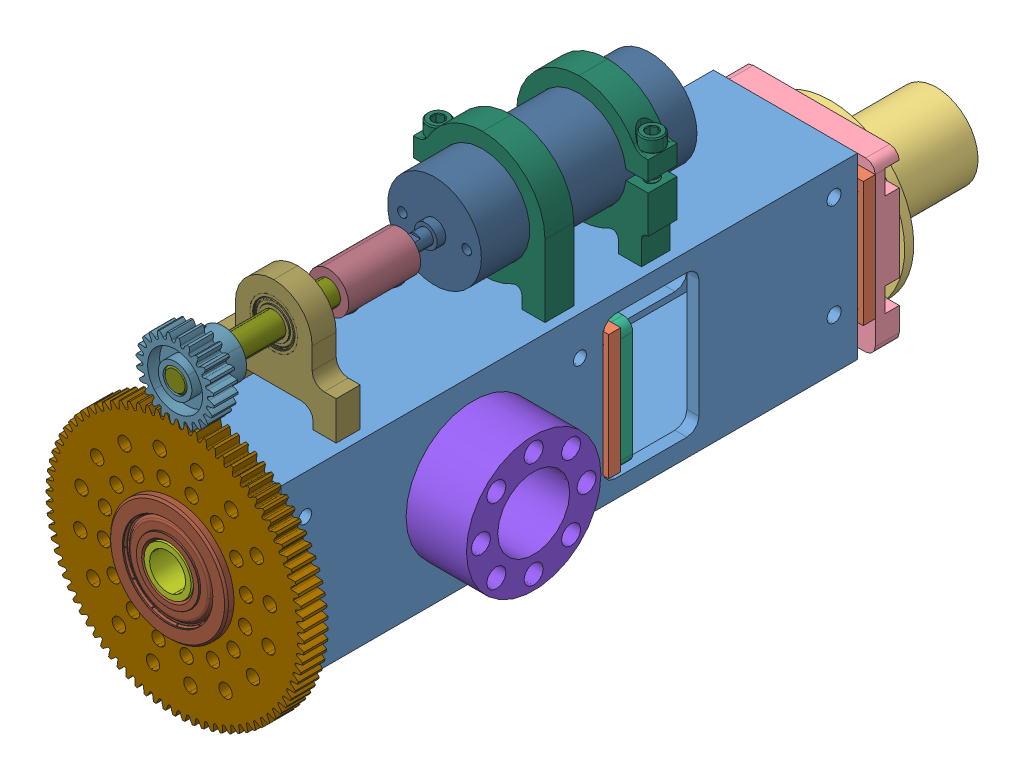
SolidWorks assembly Link 3 final, configuration Default. Lengths in mm.
Overall size (82.13 100.25 203.31).
24 component instances, 16 part files, 59 mates.
Components (placement in the parent):
- L3v1 Base-1: L3v1 Base [Default] at (8.4803 58.2755 10.2579) x (1 0 0) z (0 -1 0) size (38.1 152.4 47.24)
- J2v2 Angle Bracket 585508-2: J2v2 Angle Bracket 585508 [Default] at (-8.1567 59.6725 10.2579) x (0 1 0) z (-1 0 0) size (33.02 12.43 7.88)
- 12 wire slip ring-1: 12 wire slip ring [Default] at (8.4803 56.4975 -1.6671) x (0.999999 -0.001711 0) z (-0.001711 -0.999999 0) size (44 39.4 44)
- L3v1 SlipRingBlock-2: L3v1 SlipRingBlock [Default] at (8.4803 56.4975 7.0829) x (-1 0 0) z (0 -1 0) size (41.15 6.35 44.45)
- 0.5 oilite bushing-1: 0.5 oilite bushing [6338K572] at (8.4803 58.2755 69.6304) x (1 0 0) z (0 -1 0) size (22.23 12.7 22.23)
- J2v2 Angle Bracket 585508-3: J2v2 Angle Bracket 585508 [Default] at (25.1173 58.2755 77.5679) x (0 -1 0) z (1 0 0) size (33.02 12.43 7.88)
- J2v2 Angle Bracket 585508-4: J2v2 Angle Bracket 585508 [Default] at (-8.1567 58.2755 77.5679) x (0 1 0) z (-1 0 0) size (33.02 12.43 7.88)
- L3v1 Bushing Support-1: L3v1 Bushing Support [Default] at (8.4803 58.2755 71.2179) x (1 0 0) z (0 -1 0) size (41.15 3.17 33.02)
- J2v2 Angle Bracket 585508-1: J2v2 Angle Bracket 585508 [Default] at (25.1173 59.6725 10.2579) x (0 -1 0) z (1 0 0) size (33.02 12.43 7.88)
- Link3 to 4 Shaft-1: Link3 to 4 Shaft [Default] at (8.4803 58.2755 120.6844) x (0 0 -1) z (0.883354 -0.468706 0) size (105.92 12.45 12.45)
- L3v1 Spacer-1: L3v1 Spacer [Default] at (43.5069 58.2755 111.8579) x (0 1 0) z (0 0 1) size (35.56 15.98 35.56)
- 0.5 oilite bushing-2: 0.5 oilite bushing [6338K572] at (8.4803 58.2755 170.7148) x (1 0 0) z (0 1 0) size (22.23 12.7 22.23)
- 84T 32DP 1in bore plate gear-1: 84T 32DP 1in bore plate gear [Default] at (8.4803 58.2755 171.6622) x (-0.229974 -0.973197 0) z (0 0 -1) size (68.26 68.26 6.35)
- 56 rpm motor-1: 56 rpm motor [Default] at (8.4803 100.9475 103.0622) x (0 0 1) z (-1 0 0) size (74.8 24.8 24.8)
- L3v1 Bushing Support-2: L3v1 Bushing Support [Default] at (8.4803 58.2755 169.1273) x (1 0 0) z (0 1 0) size (41.15 3.17 33.02)
- J2v2 Angle Bracket 585508-9: J2v2 Angle Bracket 585508 [Default] at (-8.1567 58.2755 162.6579) x (0 -1 0) z (-1 0 0) size (33.02 12.43 7.88)
- J2v2 Angle Bracket 585508-10: J2v2 Angle Bracket 585508 [Default] at (25.1173 58.2755 162.6579) x (0 1 0) z (1 0 0) size (33.02 12.43 7.88)
- .5ID 1.125OD Flange Bearing-1: .5ID 1.125OD Flange Bearing [Default] at (8.4803 58.2755 165.7059) x (-0.115864 -0.993265 0) z (-0.993265 0.115864 0) size (31.17 7.94 31.17)
- quarter in  bearing-1: quarter in  bearing [Default] at (0.1036 124.4796 125.9706) x (1 0 0) z (0 -1 0) size (33.02 6.35 29.21)
- 4mm to quarter in coupler-1: 4mm to quarter in coupler [Default] at (-87.7616 108.8102 138.0956) x (-0.955138 -0.296162 0) z (0.296162 -0.955138 0) size (10.67 19.05 10.67)
- 24T quarter inch gear hub-1: 24T quarter inch gear hub [Default] at (36.9204 99.2447 166.1829) x (0.761841 0.647764 0) z (0 0 1) size (20.64 20.64 12.7)
- 25mm motor mount-1: 25mm motor mount [Default] at (35.0627 111.6687 83.0668) x (1 0 0) z (0 -1 0) size (34.9 7.62 35.56)
- 25mm motor mount-2: 25mm motor mount [Default] at (-18.1021 111.6687 64.5336) x (-1 0 0) z (0 -1 0) size (34.9 7.62 35.56)
- quarter in shaft 2in-2: quarter in shaft 2in [Default] at (8.4803 100.9475 120.8622) x (0.375221 0.926936 0) z (0.926936 -0.375221 0) size (6.34 50.8 6.34)
Mates (geometry in assembly coordinates):
- Coincident5: coincident anti-aligned: plane of L3v1 Base-1 through (8.4803 58.2755 10.2579) normal (0 0 -1); plane of J2v2 Angle Bracket 585508-1 through (25.1173 59.6725 10.2579) normal (0 0 1)
- Coincident7: coincident anti-aligned: plane of L3v1 Base-1 through (24.3553 37.8285 162.6579) normal (-1 0 0); plane of J2v2 Angle Bracket 585508-1 through (24.3553 49.2433 19.5136) normal (1 0 0)
- Coincident8: coincident anti-aligned: plane of L3v1 Base-1 through (-7.3947 37.8285 162.6579) normal (1 0 0); plane of J2v2 Angle Bracket 585508-2 through (-7.3947 70.1018 19.5136) normal (-1 0 0)
- Coincident9: coincident anti-aligned: plane of L3v1 Base-1 through (8.4803 58.2755 10.2579) normal (0 0 -1); plane of J2v2 Angle Bracket 585508-2 through (-8.1567 59.6725 10.2579) normal (0 0 1)
- Coincident10: coincident aligned: plane of J2v2 Angle Bracket 585508-1 through (29.0543 76.1825 7.0829) normal (0 1 0); plane of J2v2 Angle Bracket 585508-2 through (-12.0937 76.1825 7.0829) normal (0 1 0)
- Distance2: distance = 5.715 mm aligned: plane of J2v2 Angle Bracket 585508-1 through (29.0543 76.1825 7.0829) normal (0 1 0); plane of L3v1 Base-1 through (-10.5697 81.8975 162.6579) normal (0 1 0)
- Coincident16: coincident anti-aligned: plane of J2v2 Angle Bracket 585508-1 through (25.1173 59.6725 7.0829) normal (0 0 -1); plane of L3v1 SlipRingBlock-2 through (8.4803 56.4975 7.0829) normal (0 0 1)
- Concentric4: concentric anti-aligned: circle of J2v2 Angle Bracket 585508-1; cylinder of L3v1 SlipRingBlock-2 through (25.8793 73.1429 0.7329) axis (0 0 -1) radius 1.8986
- Concentric5: concentric anti-aligned: circle of J2v2 Angle Bracket 585508-2; circle of L3v1 SlipRingBlock-2
- Coincident17: coincident anti-aligned: plane of 12 wire slip ring-1 through (8.4803 56.4975 0.7329) normal (0 0 1); plane of L3v1 SlipRingBlock-2 through (8.4803 56.4975 0.7329) normal (0 0 -1)
- Concentric6: concentric anti-aligned: cylinder of 12 wire slip ring-1 through (8.4803 56.4975 -29.6671) axis (0 0 1) radius 11; cylinder of L3v1 SlipRingBlock-2 through (8.4803 56.4975 7.0829) axis (0 0 -1) radius 11.43
- Coincident22: coincident anti-aligned: plane of L3v1 Base-1 through (-7.3947 37.8285 162.6579) normal (1 0 0); plane of J2v2 Angle Bracket 585508-4 through (-7.3947 68.7048 86.8236) normal (-1 0 0)
- Coincident23: coincident anti-aligned: plane of L3v1 Base-1 through (-7.3947 42.591 77.5679) normal (0 0 -1); plane of J2v2 Angle Bracket 585508-4 through (-8.1567 58.2755 77.5679) normal (0 0 1)
- Width2: width aligned: plane of J2v2 Angle Bracket 585508-4 through (-12.0937 74.7855 74.3929) normal (0 1 0); plane of J2v2 Angle Bracket 585508-4 through (-12.0937 41.7655 74.3929) normal (0 -1 0); plane of L3v1 Base-1 through (-10.5697 81.8975 162.6579) normal (0 1 0); plane of L3v1 Base-1 through (-10.5697 34.6535 162.6579) normal (0 -1 0)
- Coincident24: coincident anti-aligned: plane of L3v1 Base-1 through (24.3553 37.8285 162.6579) normal (-1 0 0); plane of J2v2 Angle Bracket 585508-3 through (24.3553 68.7048 86.8236) normal (1 0 0)
- Coincident25: coincident aligned: plane of J2v2 Angle Bracket 585508-3 through (25.1173 58.2755 74.3929) normal (0 0 -1); plane of J2v2 Angle Bracket 585508-4 through (-8.1567 58.2755 74.3929) normal (0 0 -1)
- Coincident26: coincident aligned: plane of J2v2 Angle Bracket 585508-3 through (29.0543 74.7855 74.3929) normal (0 1 0); plane of J2v2 Angle Bracket 585508-4 through (-12.0937 74.7855 74.3929) normal (0 1 0)
- Coincident27: coincident anti-aligned: plane of J2v2 Angle Bracket 585508-4 through (-8.1567 58.2755 74.3929) normal (0 0 -1); plane of L3v1 Bushing Support-1 through (26.5143 72.2455 74.3929) normal (0 0 1)
- Width3: width anti-aligned: plane of L3v1 Bushing Support-1 through (26.5143 74.7855 74.3929) normal (0 1 0); plane of L3v1 Bushing Support-1 through (26.5143 41.7655 74.3929) normal (0 -1 0); plane of J2v2 Angle Bracket 585508-4 through (-12.0937 41.7655 74.3929) normal (0 -1 0); plane of J2v2 Angle Bracket 585508-4 through (-12.0937 74.7855 74.3929) normal (0 1 0)
- Coincident28: coincident aligned: plane of J2v2 Angle Bracket 585508-4 through (-12.0937 41.7655 74.3929) normal (-1 0 0); plane of L3v1 Bushing Support-1 through (-12.0937 44.3055 74.3929) normal (-1 0 0)
- Coincident29: coincident anti-aligned: plane of 0.5 oilite bushing-1 through (8.4803 58.2755 71.2179) normal (0 0 1); plane of L3v1 Bushing Support-1 through (26.5143 72.2455 71.2179) normal (0 0 -1)
- Concentric7: concentric anti-aligned: cylinder of 0.5 oilite bushing-1 through (8.4803 58.2755 82.3304) axis (0 0 -1) radius 6.3627; cylinder of L3v1 Bushing Support-1 through (8.4803 58.2755 71.2179) axis (0 0 1) radius 7.9502
- Concentric8: concentric anti-aligned: cylinder of 0.5 oilite bushing-1 through (8.4803 58.2755 82.3304) axis (0 0 -1) radius 6.3627; cylinder of Link3 to 4 Shaft-1 through (8.4803 58.2755 67.7254) axis (0 0 1) radius 6.223
- Coincident30: coincident aligned: plane of 0.5 oilite bushing-1 through (8.4803 58.2755 69.6304) normal (0 0 -1); plane of Link3 to 4 Shaft-1 through (8.4803 58.2755 69.6304) normal (0 0 -1)
- Coincident31: coincident anti-aligned: plane of L3v1 Base-1 through (27.5303 34.6535 162.6579) normal (1 0 0); plane of L3v1 Spacer-1 through (27.5303 58.2755 111.8579) normal (-1 0 0)
- Concentric9: concentric anti-aligned: cylinder of L3v1 Base-1 through (27.5303 58.2755 111.8579) axis (-1 0 0) radius 9.525; cylinder of L3v1 Spacer-1 through (27.5303 58.2755 111.8579) axis (1 0 0) radius 9.525
- Concentric10: concentric anti-aligned: cylinder of L3v1 Base-1 through (27.5303 48.3973 121.7362) axis (-1 0 0) radius 2.5527; cylinder of L3v1 Spacer-1 through (27.5303 48.3973 121.7362) axis (1 0 0) radius 2.5527
- Concentric15: concentric anti-aligned: cylinder of Link3 to 4 Shaft-1 through (8.4803 58.2755 67.7254) axis (0 0 1) radius 6.223; cylinder of 84T 32DP 1in bore plate gear-1 through (8.4803 58.2755 171.6622) axis (0 0 -1) radius 14.2875
- Concentric18: concentric aligned: cylinder of Link3 to 4 Shaft-1 through (8.4803 58.2755 67.7254) axis (0 0 1) radius 6.223; cylinder of 0.5 oilite bushing-2 through (8.4803 58.2755 158.0148) axis (0 0 1) radius 6.3627
- Concentric22: concentric anti-aligned: cylinder of Link3 to 4 Shaft-1 through (8.4803 58.2755 67.7254) axis (0 0 1) radius 6.223; cylinder of 84T 32DP 1in bore plate gear-1 through (8.4803 58.2755 171.6622) axis (0 0 -1) radius 14.2875
- Concentric25: concentric anti-aligned: cylinder of 0.5 oilite bushing-2 through (8.4803 58.2755 158.0148) axis (0 0 1) radius 7.9502; cylinder of L3v1 Bushing Support-2 through (8.4803 58.2755 169.1273) axis (0 0 -1) radius 7.9502
- Parallel5: parallel aligned: plane of 12 wire slip ring-1 through (8.4803 56.4975 -29.6671) normal (0 0 -1); plane of 56 rpm motor-1 through (8.4803 100.9475 46.0622) normal (0 0 -1)
- Symmetric6: symmetric aligned: plane of L3v1 Base-1 through (27.5303 34.6535 162.6579) normal (1 0 0); plane of 56 rpm motor-1 through (-10.5697 34.6535 162.6579) normal (-1 0 0); plane of L3v1 Base-1 through (8.4803 100.9475 103.0622) normal (-1 0 0)
- Coincident68: coincident anti-aligned: plane of L3v1 Base-1 through (-7.3947 37.8285 162.6579) normal (1 0 0); plane of J2v2 Angle Bracket 585508-9 through (-7.3947 68.7048 153.4021) normal (-1 0 0)
- Coincident69: coincident aligned: plane of L3v1 Bushing Support-2 through (26.5143 74.7855 165.9523) normal (0 1 0); plane of J2v2 Angle Bracket 585508-9 through (-12.0937 74.7855 165.8329) normal (0 1 0)
- Coincident70: coincident anti-aligned: plane of L3v1 Base-1 through (8.4803 58.2755 162.6579) normal (0 0 1); plane of J2v2 Angle Bracket 585508-9 through (-8.1567 58.2755 162.6579) normal (0 0 -1)
- Coincident71: coincident anti-aligned: plane of L3v1 Base-1 through (24.3553 37.8285 162.6579) normal (-1 0 0); plane of J2v2 Angle Bracket 585508-10 through (24.3553 68.7048 153.4021) normal (1 0 0)
- Coincident72: coincident aligned: plane of L3v1 Bushing Support-2 through (26.5143 74.7855 165.9523) normal (0 1 0); plane of J2v2 Angle Bracket 585508-10 through (29.0543 74.7855 165.8329) normal (0 1 0)
- Coincident73: coincident anti-aligned: plane of L3v1 Base-1 through (8.4803 58.2755 162.6579) normal (0 0 1); plane of J2v2 Angle Bracket 585508-10 through (25.1173 58.2755 162.6579) normal (0 0 -1)
- Concentric31: concentric aligned: cylinder of 84T 32DP 1in bore plate gear-1 through (8.4803 58.2755 171.6622) axis (0 0 -1) radius 14.2875; cylinder of .5ID 1.125OD Flange Bearing-1 through (8.4803 58.2755 171.6622) axis (0 0 -1) radius 14.2875
- Coincident80: coincident anti-aligned: plane of 84T 32DP 1in bore plate gear-1 through (-24.2442 66.4973 171.6622) normal (0 0 1); plane of .5ID 1.125OD Flange Bearing-1 through (8.4803 58.2755 171.6622) normal (0 0 -1)
- Coincident86: coincident aligned: plane of Link3 to 4 Shaft-1 through (8.4803 58.2755 173.6434) normal (0 0 1); plane of .5ID 1.125OD Flange Bearing-1 through (8.4803 58.2755 173.6434) normal (0 0 1)
- Coincident91: coincident anti-aligned: plane of L3v1 Base-1 through (-10.5697 81.8975 162.6579) normal (0 1 0); plane of quarter in  bearing-1 through (24.9903 81.8975 145.5712) normal (0 -1 0)
- Concentric32: concentric aligned: cylinder of 56 rpm motor-1 through (8.4803 100.9475 46.0622) axis (0 0 1) radius 12.4; cylinder of 25mm motor mount-1 through (8.4803 100.9475 82.7422) axis (0 0 1) radius 12.5
- Coincident93: coincident anti-aligned: plane of L3v1 Base-1 through (-10.5697 81.8975 162.6579) normal (0 1 0); plane of 25mm motor mount-1 through (-8.0297 81.8975 90.3622) normal (0 -1 0)
- Concentric33: concentric anti-aligned: cylinder of 56 rpm motor-1 through (8.4803 100.9475 46.0622) axis (0 0 1) radius 12.4; cylinder of 25mm motor mount-2 through (8.4803 100.9475 64.8582) axis (0 0 -1) radius 12.5
- Coincident94: coincident anti-aligned: plane of L3v1 Base-1 through (-10.5697 81.8975 162.6579) normal (0 1 0); plane of 25mm motor mount-2 through (24.9903 81.8975 57.2382) normal (0 -1 0)
- Coincident95: coincident aligned: circle of 56 rpm motor-1; circle of 4mm to quarter in coupler-1
- Concentric36: concentric anti-aligned: cylinder of 4mm to quarter in coupler-1 through (8.4803 100.9475 112.0432) axis (0 0 1) radius 5.334; cylinder of quarter in shaft 2in-2 through (8.4803 100.9475 171.6622) axis (0 0 -1) radius 3.1712
- Coincident97: coincident anti-aligned: plane of 56 rpm motor-1 through (8.4803 100.9475 120.8622) normal (0 0 1); plane of quarter in shaft 2in-2 through (8.4803 100.9475 120.8622) normal (0 0 -1)
- GearMate2: gear = 2133.6 : 609.6 mm: cylinder of 24T quarter inch gear hub-1 through (8.4803 100.9475 158.9622) axis (0 0 1) radius 3.175; cylinder of 84T 32DP 1in bore plate gear-1 through (8.4803 58.2755 171.6622) axis (0 0 -1) radius 14.2875
- Concentric38: concentric anti-aligned: circle of 24T quarter inch gear hub-1; circle of quarter in shaft 2in-2
- Parallel7: parallel aligned: plane of 84T 32DP 1in bore plate gear-1 through (-24.2442 66.4973 171.6622) normal (0 0 1); plane of 24T quarter inch gear hub-1 through (1.6932 108.199 171.6622) normal (0 0 1)
- Coincident98: coincident aligned: plane of 24T quarter inch gear hub-1 through (1.6932 108.199 171.6622) normal (0 0 1); plane of quarter in shaft 2in-2 through (8.4803 100.9475 171.6622) normal (0 0 1)
- Coincident99: coincident aligned: plane of 84T 32DP 1in bore plate gear-1 through (-24.2442 66.4973 171.6622) normal (0 0 1); plane of 24T quarter inch gear hub-1 through (1.6932 108.199 171.6622) normal (0 0 1)
- Width4: width anti-aligned: plane of L3v1 Base-1 through (-10.5697 34.6535 162.6579) normal (-1 0 0); plane of quarter in  bearing-1 through (27.5303 34.6535 162.6579) normal (1 0 0); plane of L3v1 Base-1 through (24.9903 92.0575 145.5712) normal (1 0 0); plane of quarter in  bearing-1 through (-8.0297 92.0575 145.5712) normal (-1 0 0)
- Distance5: distance = 11.176 mm aligned: plane of 56 rpm motor-1 through (8.4803 100.9475 46.0622) normal (0 0 -1); plane of 25mm motor mount-2 through (8.4803 100.9475 57.2382) normal (0 0 -1)
- Distance6: distance = 12.7 mm aligned: plane of 25mm motor mount-1 through (8.4803 100.9475 90.3622) normal (0 0 1); plane of 56 rpm motor-1 through (8.4803 100.9475 103.0622) normal (0 0 1)
- Distance8: distance = 14.478 mm aligned: plane of quarter in  bearing-1 through (8.4803 100.9475 145.5712) normal (0 0 1); plane of 4mm to quarter in coupler-1 through (8.4803 100.9475 131.0932) normal (0 0 1)
